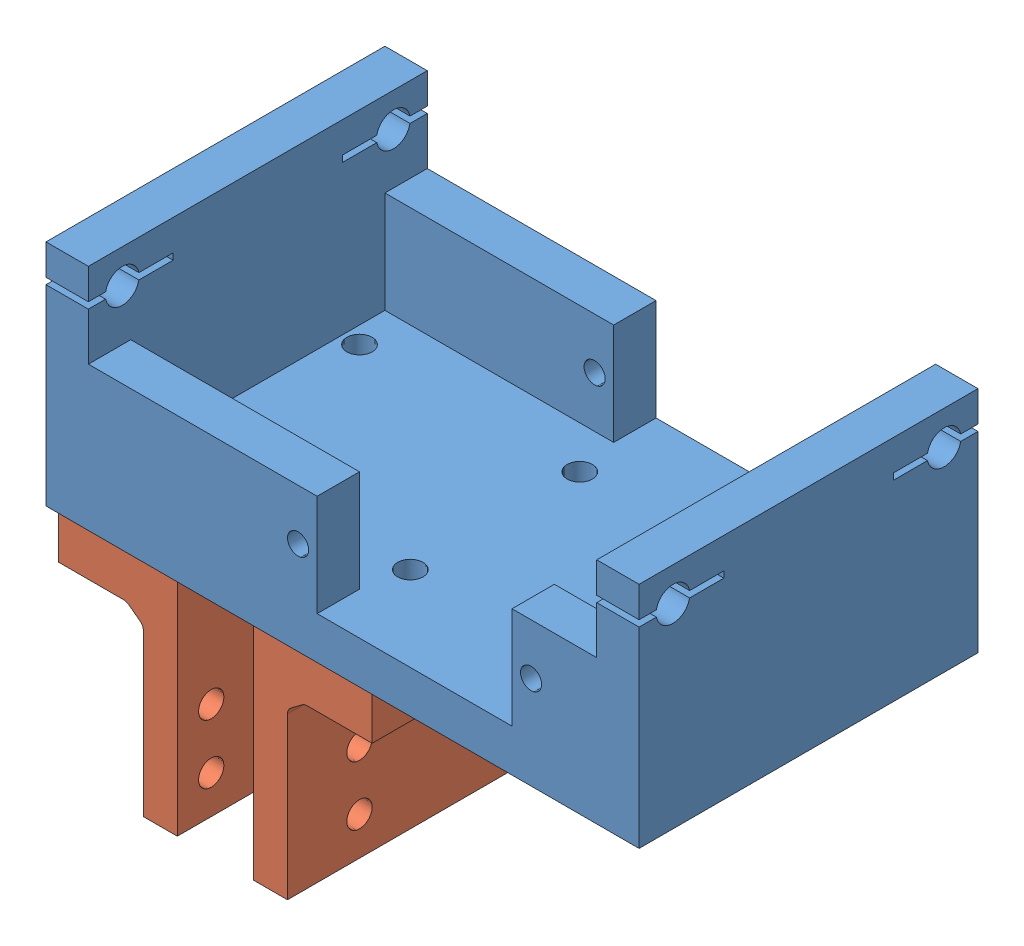
SolidWorks assembly Assem Servo Holder-Mount, configuration Default. Lengths in mm.
Overall size (70 49 40).
3 component instances, 2 part files, 6 mates.
Components (placement in the parent):
- Servo Housing-1: Servo Housing [Default] at (73.915 34.2868 26.2174) size (70 42.75 40)
- Mount Servo Housing-1: Mount Servo Housing [Default] at (65.415 12.2868 26.2174) x (-1 0 0) z (0 1 0) size (14 40 26)
- Mount Servo Housing-2: Mount Servo Housing [Default] at (52.415 12.2868 26.2174) x (1 0 0) z (0 1 0) size (14 40 26)
Mates (geometry in assembly coordinates):
- Coincident1: coincident anti-aligned: plane of Servo Housing-1 through (73.915 34.2868 26.2174) normal (0 -1 0); plane of Mount Servo Housing-1 through (65.415 34.2868 26.2174) normal (0 1 0)
- Concentric1: concentric aligned: cylinder of Mount Servo Housing-1 through (45.915 32.2868 36.2174) axis (0 -1 0) radius 1.5; cylinder of Servo Housing-1 through (45.915 61.2868 36.2174) axis (0 -1 0) radius 1.5
- Concentric2: concentric aligned: cylinder of Servo Housing-1 through (45.915 61.2868 16.2174) axis (0 -1 0) radius 1.5; cylinder of Mount Servo Housing-1 through (45.915 32.2868 16.2174) axis (0 -1 0) radius 1.5
- Coincident2: coincident anti-aligned: plane of Servo Housing-1 through (73.915 34.2868 26.2174) normal (0 -1 0); plane of Mount Servo Housing-2 through (52.415 34.2868 26.2174) normal (0 1 0)
- Concentric3: concentric aligned: cylinder of Servo Housing-1 through (71.915 61.2868 36.2174) axis (0 -1 0) radius 1.5; cylinder of Mount Servo Housing-2 through (71.915 32.2868 36.2174) axis (0 -1 0) radius 1.5
- Concentric4: concentric aligned: cylinder of Servo Housing-1 through (71.915 61.2868 16.2174) axis (0 -1 0) radius 1.5; cylinder of Mount Servo Housing-2 through (71.915 32.2868 16.2174) axis (0 -1 0) radius 1.5
